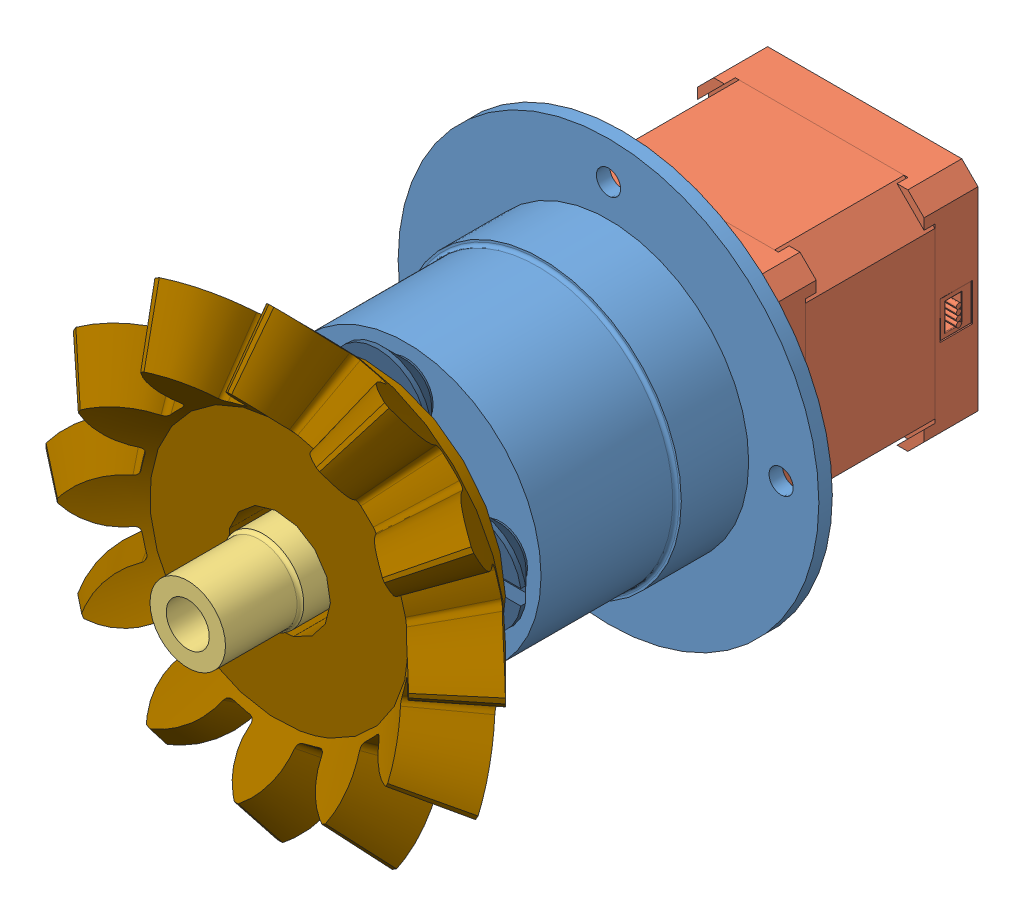
SolidWorks assembly UOM20-4A004-02, configuration Default. Lengths in mm.
Overall size (104.33 104.33 125.5).
33 component instances, 10 part files, 16 mates.
Components (placement in the parent):
- UOM20-4P027-1: UOM20-4P027 [Default] at (70.9978 25.6648 -111.1871) x (0 0 1) z (-1 0 0) size (40 78 78)
- 17HS15-1684D-HG10-AR3-1: 17HS15-1684D-HG10-AR3 [Default] at (70.9978 25.6648 -116.1871) size (42.88 42 103.5)
- UOM20-4P028-1: UOM20-4P028 [Default] at (70.9978 25.6648 -72.6871) x (0 0 1) z (-0.277193 0.960814 0) size (42 17 17)
- AXK 1528-1: AXK 1528 [Default] at (70.9978 25.6648 -69.1871) x (0 0 -1) z (0.999526 -0.030788 0) size (4 28 28)
  - AXK_1528___AS_1528___AS_1528_3-1: AXK_1528___AS_1528___AS_1528_3 [Default] x (1 0 0) z (0 -0.309017 0.951057) size (2 5 2)
  - AXK_1528___AS_1528___AS_1528_3-2: AXK_1528___AS_1528___AS_1528_3 [Default] x (1 0 0) z (0 -0.587785 0.809017) size (2 5 2)
  - AXK_1528___AS_1528___AS_1528_3-3: AXK_1528___AS_1528___AS_1528_3 [Default] x (1 0 0) z (0 -0.809017 0.587785) size (2 5 2)
  - AXK_1528___AS_1528___AS_1528_3-4: AXK_1528___AS_1528___AS_1528_3 [Default] x (1 0 0) z (0 -0.951057 0.309017) size (2 5 2)
  - AXK_1528___AS_1528___AS_1528_3-5: AXK_1528___AS_1528___AS_1528_3 [Default] x (1 0 0) z (0 -1 0) size (2 5 2)
  - AXK_1528___AS_1528___AS_1528_3-6: AXK_1528___AS_1528___AS_1528_3 [Default] x (1 0 0) z (0 -0.951057 -0.309017) size (2 5 2)
  - AXK_1528___AS_1528___AS_1528_3-7: AXK_1528___AS_1528___AS_1528_3 [Default] x (1 0 0) z (0 -0.809017 -0.587785) size (2 5 2)
  - AXK_1528___AS_1528___AS_1528_3-8: AXK_1528___AS_1528___AS_1528_3 [Default] x (1 0 0) z (0 -0.587785 -0.809017) size (2 5 2)
  - AXK_1528___AS_1528___AS_1528_3-9: AXK_1528___AS_1528___AS_1528_3 [Default] x (1 0 0) z (0 -0.309017 -0.951057) size (2 5 2)
  - AXK_1528___AS_1528___AS_1528_3-10: AXK_1528___AS_1528___AS_1528_3 [Default] x (1 0 0) z (0 0 -1) size (2 5 2)
  - AXK_1528___AS_1528___AS_1528_3-11: AXK_1528___AS_1528___AS_1528_3 [Default] x (1 0 0) z (0 0.309017 -0.951057) size (2 5 2)
  - AXK_1528___AS_1528___AS_1528_3-12: AXK_1528___AS_1528___AS_1528_3 [Default] x (1 0 0) z (0 0.587785 -0.809017) size (2 5 2)
  - AXK_1528___AS_1528___AS_1528_3-13: AXK_1528___AS_1528___AS_1528_3 [Default] x (1 0 0) z (0 0.809017 -0.587785) size (2 5 2)
  - AXK_1528___AS_1528___AS_1528_3-14: AXK_1528___AS_1528___AS_1528_3 [Default] x (1 0 0) z (0 0.951057 -0.309017) size (2 5 2)
  - AXK_1528___AS_1528___AS_1528_3-15: AXK_1528___AS_1528___AS_1528_3 [Default] x (1 0 0) z (0 1 0) size (2 5 2)
  - AXK_1528___AS_1528___AS_1528_3-16: AXK_1528___AS_1528___AS_1528_3 [Default] x (1 0 0) z (0 0.951057 0.309017) size (2 5 2)
  - AXK_1528___AS_1528___AS_1528_3-17: AXK_1528___AS_1528___AS_1528_3 [Default] x (1 0 0) z (0 0.809017 0.587785) size (2 5 2)
  - AXK_1528___AS_1528___AS_1528_3-18: AXK_1528___AS_1528___AS_1528_3 [Default] x (1 0 0) z (0 0.587785 0.809017) size (2 5 2)
  - AXK_1528___AS_1528___AS_1528_3-19: AXK_1528___AS_1528___AS_1528_3 [Default] x (1 0 0) z (0 0.309017 0.951057) size (2 5 2)
  - AXK_1528___AS_1528___AS_1528_3-20: AXK_1528___AS_1528___AS_1528_3 [Default] at origin size (2 5 2)
  - AXK_1528___AS_1528___AS_1528_24-1: AXK_1528___AS_1528___AS_1528_24 [Default] at origin size (1 28 28)
  - AXK_1528___AS_1528___AS_1528_26-1: AXK_1528___AS_1528___AS_1528_26 [Default] at origin size (1 28 28)
  - AXK_1528___AS_1528___AS_1528_28-1: AXK_1528___AS_1528___AS_1528_28 [Default] at origin size (1.6 28 28)
- 1.5mm spacer-1: 1.5mm spacer [Default] at (70.9978 25.6648 -65.6871) x (0.99936 -0.03578 0) z (0 0 1) size (28 28 1.5)
- straight miter gear_am-1: straight miter gear_am [PreviewCfg] at (70.9978 25.6648 -58.1998) x (0 0 1) z (0.277193 -0.960814 0) size (25.36 84.27 84.27)
- flat head screw_am-1: flat head screw_am [PreviewCfg] at (70.9978 43.1648 -65.8871) x (0 0 -1) z (1 0 0) size (40 18.3 18.08)
- flat head screw_am-2: flat head screw_am [PreviewCfg] at (88.4978 25.6648 -65.8871) x (0 0 -1) z (1 0 0) size (40 18.3 18.08)
- flat head screw_am-3: flat head screw_am [PreviewCfg] at (70.9978 8.1648 -65.8871) x (0 0 -1) z (1 0 0) size (40 18.3 18.08)
- flat head screw_am-4: flat head screw_am [PreviewCfg] at (53.4978 25.6648 -65.8871) x (0 0 -1) z (1 0 0) size (40 18.3 18.08)
Mates (geometry in assembly coordinates):
- Concentric10: concentric aligned: cylinder of UOM20-4P027-1 through (70.9978 25.6648 -175.2905) axis (0 0 -1) radius 21; cylinder of 17HS15-1684D-HG10-AR3-1 through (70.9978 25.6648 -76.1871) axis (0 0 -1) radius 21
- Concentric11: concentric aligned: cylinder of UOM20-4P027-1 through (70.9978 43.1648 -71.1871) axis (0 0 1) radius 2.25; cylinder of 17HS15-1684D-HG10-AR3-1 through (70.9978 43.1648 -76.1871) axis (0 0 1) radius 2.25
- Coincident5: coincident anti-aligned: plane of UOM20-4P027-1 through (70.9978 46.6648 -76.1871) normal (0 0 -1); plane of 17HS15-1684D-HG10-AR3-1 through (70.9978 25.6648 -76.1871) normal (0 0 1)
- Coincident14: coincident anti-aligned: plane of UOM20-4P027-1 through (70.9978 34.1648 -71.1871) normal (0 0 1); plane of AXK 1528-1/AXK_1528___AS_1528___AS_1528_24-1 through (71.2287 33.1612 -71.1871) normal (0 0 -1)
- Concentric17: concentric aligned: cylinder of 17HS15-1684D-HG10-AR3-1 through (70.9978 25.6648 -68.8871) axis (0 0 -1) radius 4; cylinder of UOM20-4P028-1 through (70.9978 25.6648 -30.6871) axis (0 0 -1) radius 4
- Distance2: distance = 1.5 mm anti-aligned: plane of 17HS15-1684D-HG10-AR3-1 through (70.9978 25.6648 -74.1871) normal (0 0 1); plane of UOM20-4P028-1 through (70.9978 25.6648 -72.6871) normal (0 0 -1)
- Concentric23: concentric anti-aligned: cylinder of UOM20-4P028-1 through (70.9978 25.6648 -67.6871) axis (0 0 -1) radius 7.5; cylinder of AXK 1528-1/AXK_1528___AS_1528___AS_1528_28-1 through (70.9978 25.6648 -69.9871) axis (0 0 1) radius 7.5
- Concentric241: concentric aligned: cylinder of UOM20-4P028-1 through (70.9978 25.6648 -30.6871) axis (0 0 -1) radius 7.5; cylinder of 1.5mm spacer-1 through (70.9978 25.6648 -64.1871) axis (0 0 -1) radius 14
- Coincident15: coincident anti-aligned: plane of UOM20-4P028-1 through (70.9978 25.6648 -65.6871) normal (0 0 1); plane of 1.5mm spacer-1 through (70.9978 25.6648 -65.6871) normal (0 0 -1)
- Concentric2586: concentric anti-aligned: cylinder of UOM20-4P028-1 through (70.9978 25.6648 -30.6871) axis (0 0 -1) radius 7.5; cylinder of straight miter gear_am-1 through (70.9978 25.6648 -64.1871) axis (0 0 1) radius 25.4
- Parallel10: parallel aligned: plane of UOM20-4P028-1 through (62.0826 20.4908 -72.7582) normal (-0.277193 0.960814 0); plane of straight miter gear_am-1 through (71.6908 23.2627 -21.813) normal (-0.277193 0.960814 0)
- Coincident30: coincident anti-aligned: plane of 1.5mm spacer-1 through (70.9978 25.6648 -64.1871) normal (0 0 1); plane of straight miter gear_am-1 through (70.9978 25.6648 -64.1871) normal (0 0 -1)
- Coincident31: coincident aligned: cone of UOM20-4P027-1 through (70.9978 43.1648 -71.1871) axis (0 0 -1); cone of flat head screw_am-1 through (70.9978 43.1648 -66.7371) axis (0 0 -1)
- Coincident32: coincident aligned: cone of UOM20-4P027-1 through (88.4978 25.6648 -71.1871) axis (0 0 -1); cone of flat head screw_am-2 through (88.4978 25.6648 -66.7371) axis (0 0 -1)
- Coincident33: coincident aligned: cone of UOM20-4P027-1 through (70.9978 8.1648 -71.1871) axis (0 0 -1); cone of flat head screw_am-3 through (70.9978 8.1648 -66.7371) axis (0 0 -1)
- Coincident34: coincident aligned: cone of UOM20-4P027-1 through (53.4978 25.6648 -71.1871) axis (0 0 -1); cone of flat head screw_am-4 through (53.4978 25.6648 -66.7371) axis (0 0 -1)
